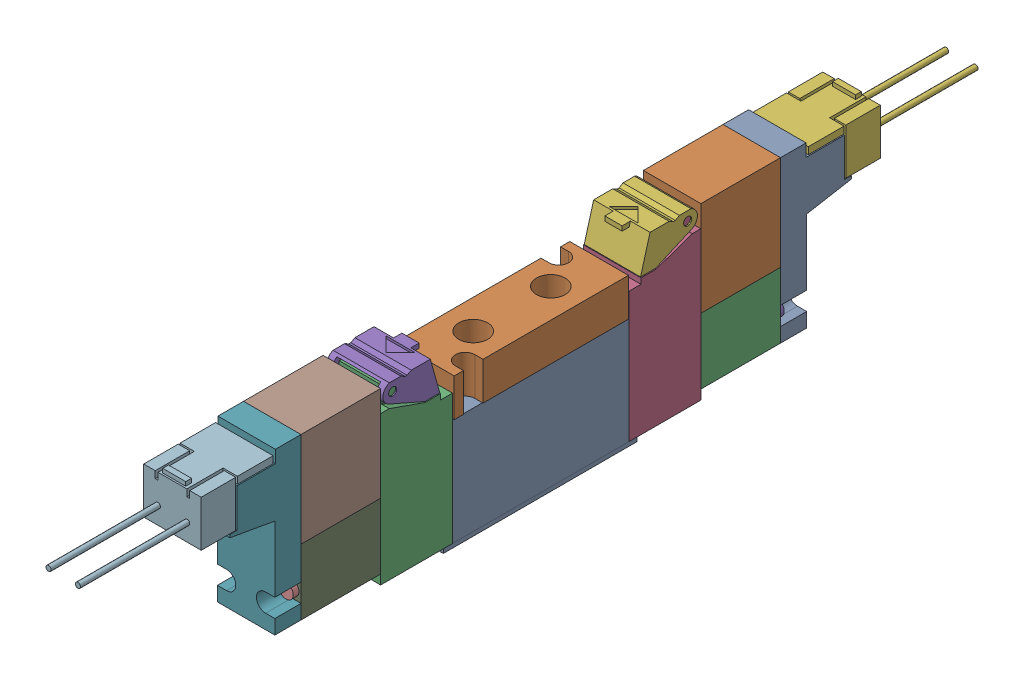
SolidWorks assembly 4GA120-M5-E01-4_4GA129-M5-E-3, configuration Default. Lengths in mm.
Overall size (10.2 30.4 156.1).
12 component instances, 6 part files, 0 mates.
Components (placement in the parent):
- 4GA120-M5-E01-4_D_100000_4G-Coil-SubASSY_01(EDC-E-H)-1: 4GA120-M5-E01-4_D_100000_4G-Coil-SubASSY_01(EDC-E-H) [Default] at (0 2.46 -27.85) size (10 27.94 50.2)
  - 4GA120-M5-E01-4_D_000102_4GcoilEDC_00(Default)-1: 4GA120-M5-E01-4_D_000102_4GcoilEDC_00(Default) [Default] at origin size (10 27.94 26.2)
  - 4GA120-M5-E01-4_D_000123_4GSocketAssyE_00(Default)-1: 4GA120-M5-E01-4_D_000123_4GSocketAssyE_00(Default) [Default] at (0 22.17 -25.2) size (10 8.7 31.5)
- 4GA120-M5-E01-4_D_100000_4G-Coil-SubASSY_01(EDC-E-H)-1-1: 4GA120-M5-E01-4_D_100000_4G-Coil-SubASSY_01(EDC-E-H)-1 [Default] at (0 2.46 27.85) x (-1 0 0) z (0 0 -1) size (10 27.94 50.2)
  - 4GA120-M5-E01-4_D_000102_4GcoilEDC_00(Default)-1: 4GA120-M5-E01-4_D_000102_4GcoilEDC_00(Default) [Default] at origin size (10 27.94 26.2)
  - 4GA120-M5-E01-4_D_000123_4GSocketAssyE_00(Default)-1: 4GA120-M5-E01-4_D_000123_4GSocketAssyE_00(Default) [Default] at (0 22.17 -25.2) size (10 8.7 31.5)
- 4GA120-M5-E01-4_D_000091_4G1Body_00(Default)-1: 4GA120-M5-E01-4_D_000091_4G1Body_00(Default) [Default] at origin size (10 19.4 33.7)
- 4GA120-M5-E01-4_D_000100_4G1PlateM5_00(Default)-1: 4GA120-M5-E01-4_D_000100_4G1PlateM5_00(Default) [Default] at (0 19.4 0) size (10.2 6.6 30.3)
- 4GA120-M5-E01-4_D_000097_4G1PistonAssy_00(Default)-1: 4GA120-M5-E01-4_D_000097_4G1PistonAssy_00(Default) [Default] at (0 0.8 15.35) x (-1 0 0) z (0 0 -1) size (10 28.72 12.5)
- 4GA120-M5-E01-4_D_000097_4G1PistonAssy_00(Default)-2: 4GA120-M5-E01-4_D_000097_4G1PistonAssy_00(Default) [Default] at (0 0.8 -15.35) size (10 28.72 12.5)
- 4GA120-M5-E01-4_D_000094_4G1ManualCover_00(Default)-1: 4GA120-M5-E01-4_D_000094_4G1ManualCover_00(Default) [Default] at (0 28.8 25.65) x (-1 0 0) z (0 0 -1) size (9.8 5.9 9.89)
- 4GA120-M5-E01-4_D_000094_4G1ManualCover_00(Default)-2: 4GA120-M5-E01-4_D_000094_4G1ManualCover_00(Default) [Default] at (0 28.8 -25.65) size (9.8 5.9 9.89)
